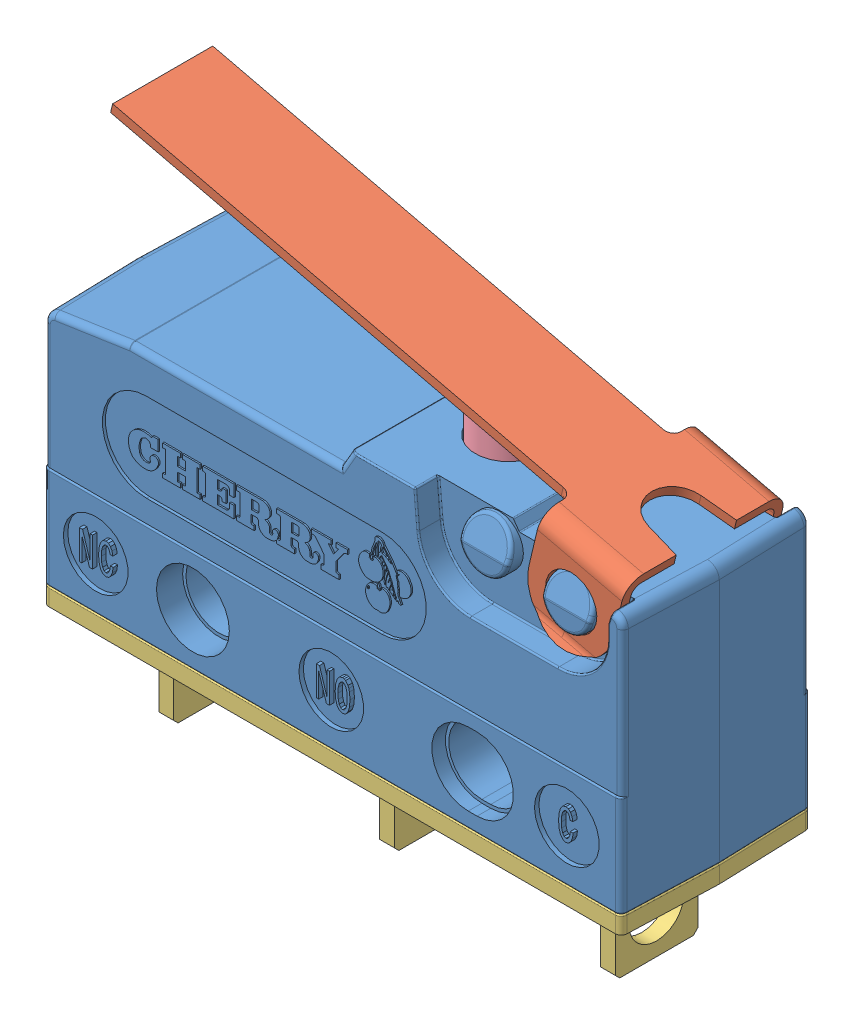
SolidWorks assembly db1c-a1lb, configuration Default. Lengths in mm.
Overall size (19.85 18.16 6.45).
4 component instances, 4 part files, 12 mates.
Components (placement in the parent):
- db1c-a1lb_1-1: db1c-a1lb_1 [Default] at (0.6654 -1.3374 3.6764) size (19.85 9.14 6.45)
- db1c-a1lb_2-1: db1c-a1lb_2 [Default] at (0.8164 -1.6805 3.6764) x (0.999683 0.025181 0) z (0 0 1) size (18.42 7.79 5.79)
- db1c-a1lb_3-1: db1c-a1lb_3 [Default] at (0.6654 -1.3374 3.6764) size (19.85 3.95 6.45)
- db1c-a1lb_4-1: db1c-a1lb_4 [Default] at (0.6654 -1.5336 3.6764) size (2.17 4 2.17)
Mates (geometry in assembly coordinates):
- Concentric2: concentric: cylinder of db1c-a1lb_2-1 through (13.0154 4.8251 1.5701) axis (0 0 1) radius 0.8725; cylinder of db1c-a1lb_1-1 through (13.0154 4.8251 3.6764) axis (0 0 -1) radius 0.8375
- Width1: width: plane of db1c-a1lb_1-1 through (0.6654 -1.3374 1.2884) normal (0 0 -1); plane of db1c-a1lb_1-1 through (0.6654 -1.3374 6.0644) normal (0 0 1); plane of db1c-a1lb_2-1 through (12.7616 3.7548 6.4064) normal (0 0 1); plane of db1c-a1lb_2-1 through (12.7616 3.7548 0.9464) normal (0 0 -1)
- Coincident1: coincident: plane of db1c-a1lb_1-1 through (-4.5346 -3.0874 3.6764) normal (0 -1 0); plane of db1c-a1lb_3-1 through (12.9354 -3.0874 3.6764) normal (0 1 0)
- Coincident2: coincident: line of db1c-a1lb_1-1 through (-4.5346 4.5695 3.6764) axis (0 -1 0); line of db1c-a1lb_3-1 through (-4.5346 -3.1374 3.6764) axis (0 -1 0)
- Coincident3: coincident: line of db1c-a1lb_1-1 through (15.3154 -3.0374 3.6764) axis (0 1 0); line of db1c-a1lb_3-1 through (15.3154 -3.1374 3.6764) axis (0 -1 0)
- Concentric3: concentric: cylinder of db1c-a1lb_1-1 through (8.1654 5.4626 3.6764) axis (0 -1 0) radius 1.1325; cylinder of db1c-a1lb_4-1 through (8.1654 6.0264 3.6764) axis (0 1 0) radius 1.0875
- Parallel1: parallel: plane of db1c-a1lb_1-1 through (0.6654 -1.3374 3.6764) normal (0 0 1); plane of db1c-a1lb_4-1 through (0.9927 -1.6112 3.6764) normal (0 0 1)
- Tangent2: tangent: plane of db1c-a1lb_2-1 through (13.373 6.3333 1.5464) normal (-0.230709 -0.973023 0); cylinder of db1c-a1lb_4-1 through (8.4927 5.9488 3.6764) axis (0 0 -1) radius 1.5
- REST_POSITION: distance = 14 mm: plane of db1c-a1lb_3-1 through (0.6654 -1.3374 3.6764) normal (0 1 0); line of db1c-a1lb_2-1 through (-2.7404 12.6626 1.9764) axis (0 0 1)
- MAX_ACTUATION_HEIGHT: distance = 12 mm: plane of db1c-a1lb_3-1 through (0.6654 -1.3374 3.6764) normal (0 1 0); line of db1c-a1lb_2-1 through (-3.5857 10.6626 1.9764) axis (0 0 1)
- MIN_ACTUATION_HEIGHT: distance = 9.4 mm: plane of db1c-a1lb_3-1 through (0.6654 -1.3374 3.6764) normal (0 1 0); line of db1c-a1lb_2-1 through (-4.2817 8.0626 1.9764) axis (0 0 1)
- BOTTOM-OUT: distance = 7.3 mm: plane of db1c-a1lb_3-1 through (0.6654 -1.3374 3.6764) normal (0 1 0); line of db1c-a1lb_2-1 through (-4.5453 5.9626 1.9764) axis (0 0 1)
